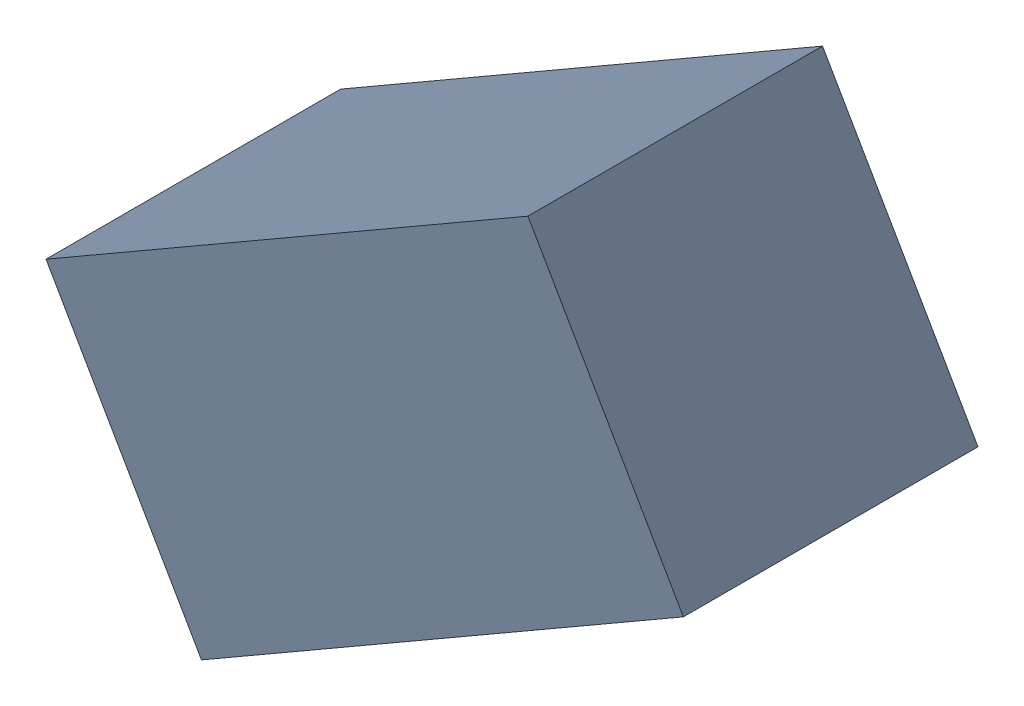
SolidWorks assembly R2_TDA2, configuration Standard. Lengths in mm.
Overall size (1.95 1.67 0.9).
2 component instances, 1 part files, 0 mates.
Components (placement in the parent):
- 885544008-1: 885544008 [Standard] at (41.8271 34.1484 0) size (1.95 1.67 0.9)
  - Extruded_15-1: Extruded_15 [Standard] at origin size (1.95 1.67 0.9)
